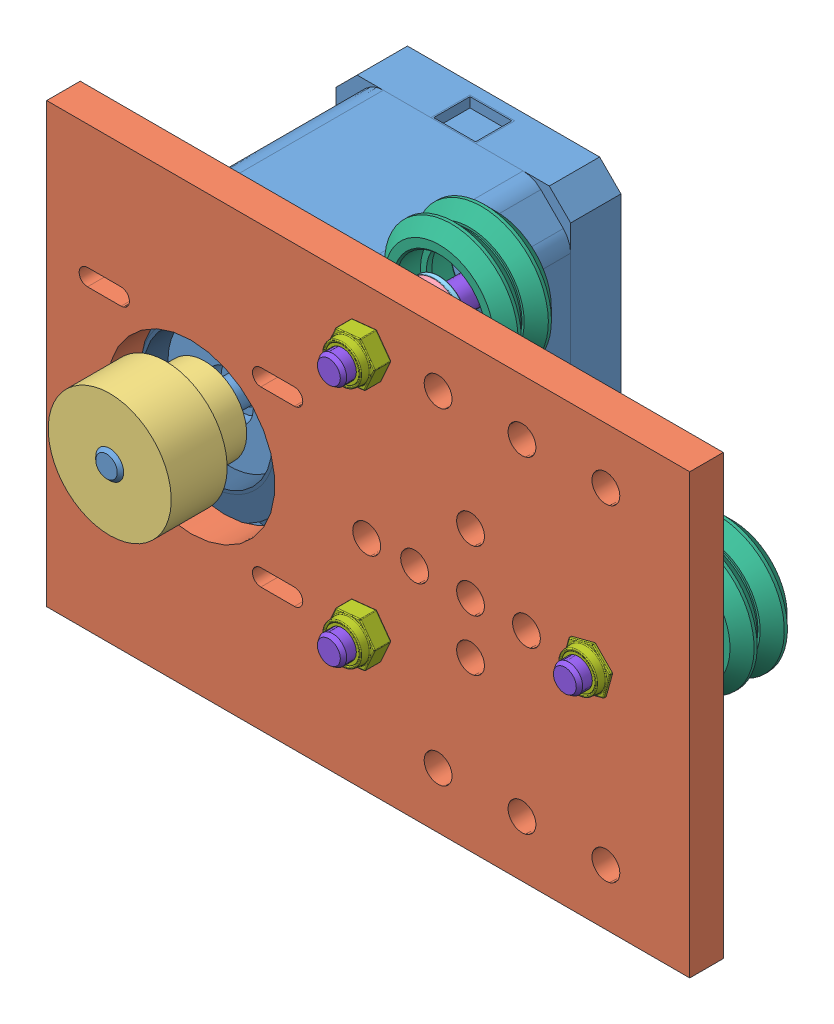
SolidWorks assembly X Motor, configuration Default. Lengths in mm.
Overall size (149.33 96.33 71).
22 component instances, 10 part files, 14 mates.
Components (placement in the parent):
- NEMA17_48-1: NEMA17_48 [Default] at (18.5315 36.8987 58.8087) size (42 42 71)
- X Stepper Mount-1: X Stepper Mount [Default] at (71.5315 36.8987 64.7087) x (1 0 0) z (0 -1 0) size (115 6 78.4)
- GT2 Pulley-1: GT2 Pulley [Default] at (18.5315 36.8987 72.2337) x (0.991394 0.130915 0) z (-0.130915 0.991394 0) size (22 17 22)
- Delrin Assembly-1: Delrin Assembly [Default] at (52.9627 66.0979 58.7087) x (0 0 1) z (0.923728 0.383049 0) size (31.75 33.75 33.75)
  - Aluminum Spacer-1: Aluminum Spacer [6mm] at origin size (6 10 10)
  - Precision Shim 10x5x1mm-1: Precision Shim 10x5x1mm [Default] at (-1 0 0) x (1 0 0) z (0 0.993706 0.112022) size (1 10 10)
  - Dual V-Wheel Delrin-1: Dual V-Wheel Delrin [Default] at (-6.115 0 0) x (0 -0.740375 0.672194) z (-1 0 0) size (23.89 23.89 10.23)
  - Nylon Insert Hex Locknut M5-1: Nylon Insert Hex Locknut M5 [Default] at (12 0 0) x (0 -0.231787 0.972767) z (1 0 0) size (7.68 8.82 4.5)
  - 5mm Low Profile Socket Head Screw-1: 5mm Low Profile Socket Head Screw [5mm x 30mm Low Profile Screw] at (-12.98 0 0) x (1 0 0) z (0 0.597414 0.801933) size (31.75 9.5 9.5)
- Delrin Assembly-2: Delrin Assembly [Default] at (52.9627 22.6994 58.7087) x (0 0 1) z (0.923728 0.383049 0) size (31.75 33.75 33.75)
  - Aluminum Spacer-1: Aluminum Spacer [6mm] at origin size (6 10 10)
  - Precision Shim 10x5x1mm-1: Precision Shim 10x5x1mm [Default] at (-1 0 0) x (1 0 0) z (0 0.993706 0.112022) size (1 10 10)
  - Dual V-Wheel Delrin-1: Dual V-Wheel Delrin [Default] at (-6.115 0 0) x (0 -0.740375 0.672194) z (-1 0 0) size (23.89 23.89 10.23)
  - Nylon Insert Hex Locknut M5-1: Nylon Insert Hex Locknut M5 [Default] at (12 0 0) x (0 -0.231787 0.972767) z (1 0 0) size (7.68 8.82 4.5)
  - 5mm Low Profile Socket Head Screw-1: 5mm Low Profile Socket Head Screw [5mm x 30mm Low Profile Screw] at (-12.98 0 0) x (1 0 0) z (0 0.597414 0.801933) size (31.75 9.5 9.5)
- Eccentric Delrin Assembly-1: Eccentric Delrin Assembly [Default] at (91.8727 36.8987 61.2087) x (0 0 -1) z (1 0 0) size (31.75 27.59 27.59)
  - Steel Eccentric Spacer-1: Steel Eccentric Spacer [6mm - Mini] at origin size (8.5 9.09 8.71)
  - Precision Shim 10x5x1mm-1: Precision Shim 10x5x1mm [Default] at (6 0 0.79) x (-1 0 0) z (0 0.812589 -0.582837) size (1 10 10)
  - Nylon Insert Hex Locknut M5-1: Nylon Insert Hex Locknut M5 [Default] at (-7 0 0.79) x (0 -0.700969 -0.713192) z (-1 0 0) size (7.68 8.82 4.5)
  - Dual V-Wheel Delrin-1: Dual V-Wheel Delrin [Default] at (11.115 0 0.79) x (0 0.169483 -0.985533) z (1 0 0) size (23.89 23.89 10.23)
  - 5mm Low Profile Socket Head Screw-1: 5mm Low Profile Socket Head Screw [5mm x 30mm Low Profile Screw] at (17.98 0 0.79) x (-1 0 0) z (0 -0.935654 -0.352919) size (31.75 9.5 9.5)
- Stepper Damper-1: Stepper Damper [Default] at (18.5317 36.8985 58.8087) x (0.707107 0.707107 0) z (0.707107 -0.707107 0) size (51.85 6.11 80.79)
Mates (geometry in assembly coordinates):
- Concentric1: concentric anti-aligned: cylinder of NEMA17_48-1 through (3.0315 52.3987 54.3087) axis (0 0 1) radius 1.5; cylinder of X Stepper Mount-1 through (3.0315 52.3987 70.7087) axis (0 0 -1) radius 1.5
- Concentric2: concentric anti-aligned: cylinder of NEMA17_48-1 through (34.0315 21.3987 54.3087) axis (0 0 1) radius 1.5; cylinder of X Stepper Mount-1 through (34.0315 21.3987 70.7087) axis (0 0 -1) radius 1.5
- Concentric3: concentric anti-aligned: cylinder of NEMA17_48-1 through (18.5315 36.8987 82.8087) axis (0 0 -1) radius 2.5; cylinder of GT2 Pulley-1 through (18.5315 36.8987 62.2337) axis (0 0 1) radius 2.5
- Concentric4: concentric aligned: cylinder of X Stepper Mount-1 through (52.9627 66.0979 70.7087) axis (0 0 -1) radius 2.5; cylinder of Delrin Assembly-1/5mm Low Profile Socket Head Screw-1 through (52.9627 66.0979 45.7287) axis (0 0 -1) radius 2.5
- Coincident3: coincident anti-aligned: plane of X Stepper Mount-1 through (71.5315 36.8987 64.7087) normal (0 0 -1); plane of Delrin Assembly-1/Aluminum Spacer-1 through (52.9627 66.0979 64.7087) normal (0 0 1)
- Concentric5: concentric aligned: cylinder of X Stepper Mount-1 through (52.9627 22.6994 70.7087) axis (0 0 -1) radius 2.5; cylinder of Delrin Assembly-2/5mm Low Profile Socket Head Screw-1 through (52.9627 22.6994 45.7287) axis (0 0 -1) radius 2.5
- Coincident4: coincident anti-aligned: plane of X Stepper Mount-1 through (71.5315 36.8987 64.7087) normal (0 0 -1); plane of Delrin Assembly-2/Aluminum Spacer-1 through (52.9627 22.6994 64.7087) normal (0 0 1)
- Coincident5: coincident anti-aligned: plane of X Stepper Mount-1 through (71.5315 36.8987 64.7087) normal (0 0 -1); plane of Eccentric Delrin Assembly-1/Steel Eccentric Spacer-1 through (91.8727 36.8987 64.7087) normal (0 0 1)
- Concentric6: concentric aligned: cylinder of X Stepper Mount-1 through (92.6627 36.8987 70.7087) axis (0 0 -1) radius 3.6; cylinder of Eccentric Delrin Assembly-1/5mm Low Profile Socket Head Screw-1 through (92.6627 36.8987 43.2287) axis (0 0 -1) radius 2.5
- Coincident6: coincident anti-aligned: plane of NEMA17_48-1 through (18.5315 36.8987 58.8087) normal (0 0 1); plane of Stepper Damper-1 through (18.5317 36.8985 58.8087) normal (0 0 -1)
- Concentric7: concentric anti-aligned: cylinder of NEMA17_48-1 through (3.0315 52.3987 54.3087) axis (0 0 1) radius 1.5; cylinder of Stepper Damper-1 through (3.0319 52.3982 58.8087) axis (0 0 -1) radius 1.75
- Concentric8: concentric anti-aligned: circle of NEMA17_48-1; cylinder of Stepper Damper-1 through (34.0315 21.3987 58.8087) axis (0 0 -1) radius 1.75
- Coincident7: coincident: plane of X Stepper Mount-1 through (71.5315 36.8987 64.7087) normal (0 0 -1); line of Stepper Damper-1 through (33.213 56.3136 64.7087) axis (-0.978839 -0.204634 0)
- Coincident8: coincident aligned: circle of NEMA17_48-1; plane of GT2 Pulley-1 through (18.5315 36.8987 82.2337) normal (0 0 1)
